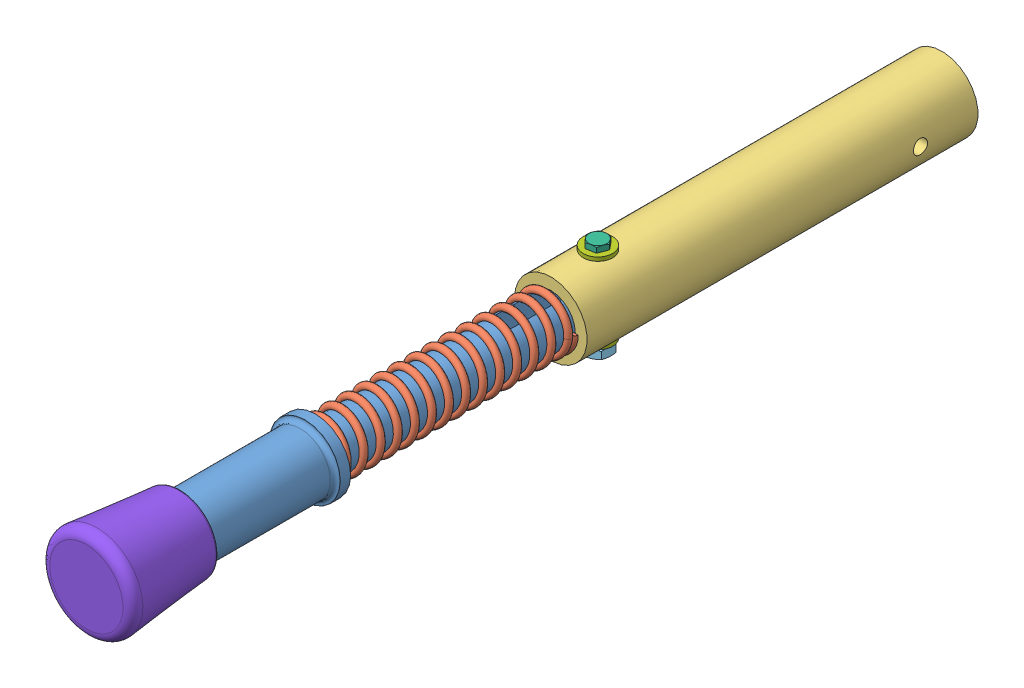
SolidWorks assembly RR2 Leg Subassembly, configuration Default. Lengths in mm.
Overall size (29.42 28.7 230.63).
9 component instances, 8 part files, 16 mates.
Components (placement in the parent):
- RR2 Leg Rod-1: RR2 Leg Rod [Default] at (-32.4466 0 163.322) x (-1 0 0) z (0 -1 0) size (19.05 163.32 19.05)
- RR2 Spring-1: RR2 Spring [9657K421] at (-32.6702 -0.1472 114.3) size (17.2 17.2 64.41)
- RR2 Leg Tube-1: RR2 Leg Tube [Default] at (-32.4466 0 50.8) x (0 -1 0) z (1 0 0) size (19.56 105.41 19.56)
- RR2 4 Bushing-1: RR2 4 Bushing [94639A664] at (-32.4466 -0.0931 38.1) x (0.887003 0 -0.461764) z (0 1 0) size (4.76 4.76 19.05)
- RR2 4 Nut-2: RR2 4 Nut [90101A004] at (-32.4466 -13.6074 38.1) x (0.996652 0 0.081761) z (-0.081761 0 0.996652) size (6.35 2.86 7.33)
- RR2 4 Screw-1: RR2 4 Screw [92314A115] at (-32.4466 10.8477 38.1) x (0.159771 0 0.987154) z (0 1 0) size (4.76 5.5 27.24)
- RR2 4 Washer-1: RR2 4 Washer [96659A101] at (-32.4466 -10.8293 38.1) x (0.112204 0 0.993685) z (-0.993685 0 0.112204) size (7.92 1.02 7.92)
- RR2 4 Washer-2: RR2 4 Washer [96659A101] at (-32.4466 9.8317 38.1) x (-0.013346 0 0.999911) z (-0.999911 0 -0.013346) size (7.92 1.02 7.92)
- RR2 Boot-1: RR2 Boot [Default] at (-32.4466 0 176.022) x (1 0 0) z (0 1 0) size (29.42 25.4 27.68)
Mates (geometry in assembly coordinates):
- Coincident2: coincident anti-aligned: plane of RR2 Leg Rod-1 through (-32.4466 0 0) normal (0 0 -1); plane of assembly through (0 0 0) normal (0 0 1)
- Concentric2: concentric anti-aligned: cylinder of RR2 Leg Rod-1 through (-32.4466 0 114.3) axis (0 0 -1) radius 6.223; cylinder of RR2 Leg Tube-1 through (-32.4466 0 -54.61) axis (0 0 1) radius 5.7785
- Coincident5: coincident anti-aligned: plane of RR2 Leg Rod-1 through (-32.4466 0 114.3) normal (0 0 -1); plane of RR2 Spring-1 through (-32.6702 -0.1472 114.3) normal (0 0 1)
- Concentric3: concentric anti-aligned: cylinder of RR2 4 Bushing-1 through (-32.4466 9.4319 38.1) axis (0 -1 0) radius 1.4605; cylinder of RR2 4 Washer-2 through (-32.4466 9.8317 38.1) axis (0 1 0) radius 1.5875
- Concentric4: concentric anti-aligned: cylinder of RR2 4 Bushing-1 through (-32.4466 9.4319 38.1) axis (0 -1 0) radius 1.4605; cylinder of RR2 4 Washer-1 through (-32.4466 -10.8293 38.1) axis (0 1 0) radius 1.5875
- Concentric5: concentric aligned: cylinder of RR2 4 Bushing-1 through (-32.4466 9.4319 38.1) axis (0 -1 0) radius 1.4605; cylinder of RR2 4 Nut-2 through (-32.4466 -9.5593 38.1) axis (0 -1 0) radius 1.9297
- Concentric6: concentric aligned: cylinder of RR2 Leg Tube-1 through (-32.4466 9.779 38.1) axis (0 -1 0) radius 2.54; cylinder of RR2 4 Bushing-1 through (-32.4466 9.4319 38.1) axis (0 -1 0) radius 2.3813
- Concentric7: concentric aligned: circle of RR2 4 Bushing-1; circle of RR2 4 Screw-1
- Coincident7: coincident anti-aligned: plane of RR2 4 Nut-2 through (-32.1468 -10.8293 34.4461) normal (0 1 0); plane of RR2 4 Washer-1 through (-32.4466 -10.8293 38.1) normal (0 -1 0)
- Coincident9: coincident anti-aligned: plane of RR2 4 Screw-1 through (-34.1842 10.8477 35.969) normal (0 -1 0); plane of RR2 4 Washer-2 through (-32.4466 10.8477 38.1) normal (0 1 0)
- Concentric8: concentric aligned: cylinder of RR2 Leg Rod-1 through (-32.4466 9.525 38.1) axis (0 -1 0) radius 2.6353; cylinder of RR2 4 Bushing-1 through (-32.4466 9.4319 38.1) axis (0 -1 0) radius 2.3813
- Coincident11: coincident anti-aligned: plane of RR2 Spring-1 through (-32.6702 -0.1472 50.8) normal (0 0 -1); plane of RR2 Leg Tube-1 through (-32.4466 0 50.8) normal (0 0 1)
- Coincident12: coincident anti-aligned: plane of RR2 Leg Rod-1 through (-32.4466 0 163.322) normal (0 -1 0); plane of assembly through (0 0 0) normal (0 1 0)
- Coincident14: coincident anti-aligned: plane of RR2 Leg Tube-1 through (-32.4466 0 50.8) normal (0 -1 0); plane of assembly through (0 0 0) normal (0 1 0)
- Concentric9: concentric anti-aligned: cylinder of RR2 Leg Rod-1 through (-32.4466 0 117.094) axis (0 0 1) radius 8.128; cylinder of RR2 Boot-1 through (-32.4466 0 163.322) axis (0 0 -1) radius 8.128
- Coincident15: coincident anti-aligned: plane of RR2 Leg Rod-1 through (-32.4466 0 163.322) normal (0 0 1); plane of RR2 Boot-1 through (-32.4466 0 163.322) normal (0 0 -1)
